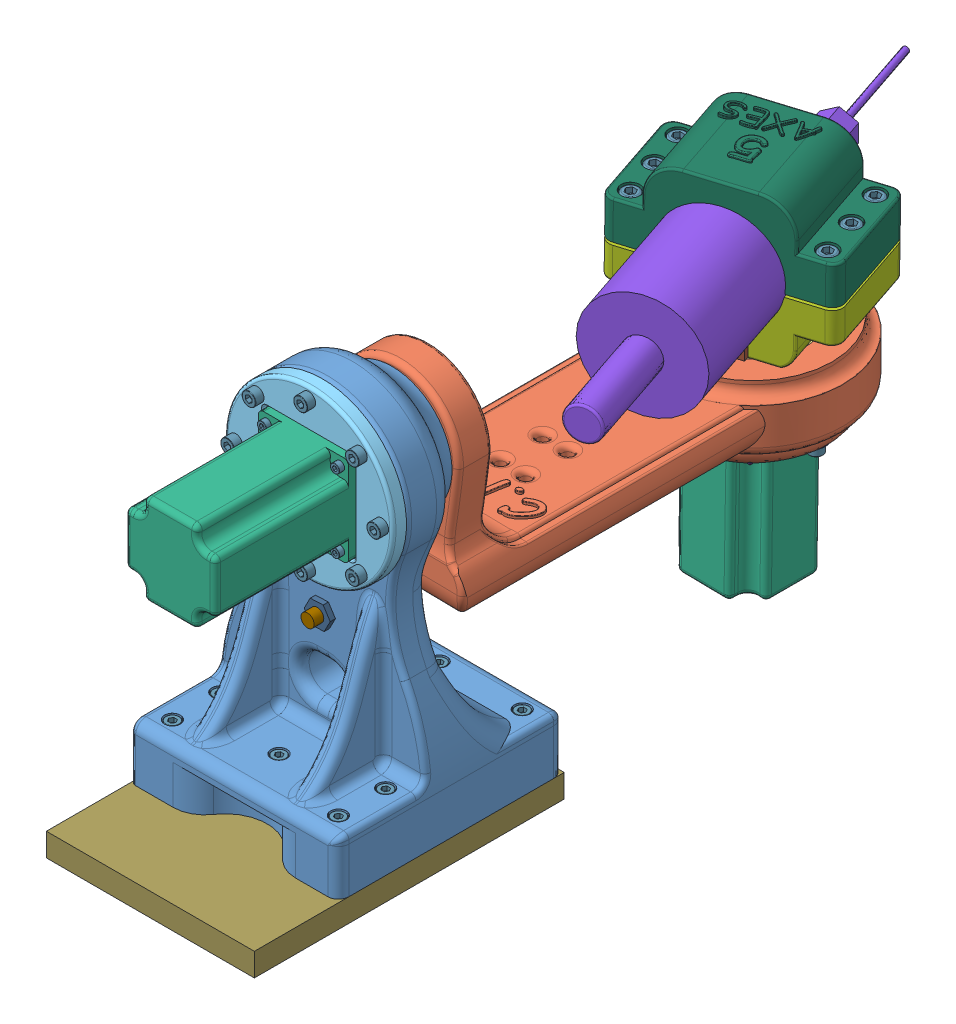
SolidWorks assembly tete 5 axes en mouvement, configuration Défaut. Lengths in mm.
Overall size (248.49 362.56 807.59).
70 component instances, 17 part files, 151 mates.
Components (placement in the parent):
- piece 1-1-1: piece 1-1 [Défaut] at (38.8935 -19.616 413.569) size (199.42 340.56 214.97)
- Pièce3^tete 5 axes-1: Pièce3^tete 5 axes [Défaut] at (37.1302 -19.7902 335.8451) x (0.999871 -0.01606 0) z (-0.01606 -0.999871 0) size (175.54 481.72 211.7)
- roulement piece 1-1: roulement piece 1 [Défaut] at (27.1666 90.0863 443.8984) x (-0.999728 0.023318 0) z (0 0 1) size (105 105 20)
- Pièce 1-3-1: Pièce 1-3 [Défaut] at (37.1302 -19.7902 463.8984) x (0.999871 -0.01606 0) z (0 0 1) size (80 80 10)
- Pièce1-2-1: Pièce1-2 [Défaut] at (38.8935 -19.616 479.8984) size (160 160 13)
- moteur-1: moteur [Défaut] at (38.8935 106.5111 487.8984) size (86 86 171)
- Pièce 2-3-1: Pièce 2-3 [Défaut] at (121.7091 79.1642 318.6411) x (0.948952 -0.015242 -0.315051) z (-0.01606 -0.999871 0) size (180 100.51 109.64)
- broche-1: broche [Défaut] at (79.1434 89.2514 227.1649) x (-0.949054 -0.010165 0.31495) z (-0.315011 0.00506 -0.949075) size (100 100 485)
- capteur fin de cource-3: capteur fin de cource [Défaut] at (39.937 11.1854 170.3888) x (0.960842 -0.015433 -0.276667) z (0.01606 0.999871 0) size (12.5 12.5 63.5)
- ecrous capteur fin de cource-6: ecrous capteur fin de cource [Défaut] at (40.8266 -18.5494 163.5015) x (0.782352 -0.012566 0.62271) z (-0.01606 -0.999871 0) size (24.76 22 5)
- ecrous capteur fin de cource-7: ecrous capteur fin de cource [Défaut] at (41.2392 7.1473 164.5494) x (0.738232 -0.011857 0.674443) z (-0.01606 -0.999871 0) size (24.76 22 5)
- Pièce 2-4-1: Pièce 2-4 [Défaut] at (53.925 82.1555 114.3268) x (0.948952 -0.015242 -0.315051) z (0.315011 -0.00506 0.949075) size (45 18.19 53)
- Pièce11^Assemblage1-1: Pièce11^Assemblage1 [Défaut] at (27.1666 -170.472 -625.5807) x (-1 0 0) z (0 1 0) size (198 294.97 22)
- Pièce1^tete 5 axes en mouvement-1: Pièce1^tete 5 axes en mouvement [Défaut] at (37.1302 -19.7902 413.5676) x (0.999871 -0.01606 0) z (0 0 1) size (56 23.61 15.05) (virtual)
- capteur fin de cource-4: capteur fin de cource [Défaut] at (12.6617 -27.2437 485.6222) x (-0.49685 -0.867836 0) z (0 0 1) size (12.5 12.5 63.5)
- ecrous capteur fin de cource-8: ecrous capteur fin de cource [Défaut] at (38.8935 -32.0352 479.8984) size (24.76 22 5)
- ecrous capteur fin de cource-9: ecrous capteur fin de cource [Défaut] at (38.8935 -32.0352 433.8984) size (24.76 22 5)
- socket head cap screw_iso-1: socket head cap screw_iso [ISO 4762 M8 x 12 - 12N] at (-42.3636 90.0863 500.8984) x (0 0 -1) z (1 0 0) size (20 13 13)
- socket head cap screw_iso-2: socket head cap screw_iso [ISO 4762 M8 x 12 - 12N] at (-21.9987 139.2516 500.8984) x (0 0 -1) z (1 0 0) size (20 13 13)
- socket head cap screw_iso-3: socket head cap screw_iso [ISO 4762 M8 x 12 - 12N] at (27.1666 159.6165 500.8984) x (0 0 -1) z (1 0 0) size (20 13 13)
- socket head cap screw_iso-4: socket head cap screw_iso [ISO 4762 M8 x 12 - 12N] at (76.3319 139.2516 500.8984) x (0 0 -1) z (1 0 0) size (20 13 13)
- socket head cap screw_iso-5: socket head cap screw_iso [ISO 4762 M8 x 12 - 12N] at (-21.9987 40.921 500.8984) x (0 0 -1) z (1 0 0) size (20 13 13)
- socket head cap screw_iso-6: socket head cap screw_iso [ISO 4762 M8 x 12 - 12N] at (27.1666 20.5561 500.8984) x (0 0 -1) z (1 0 0) size (20 13 13)
- socket head cap screw_iso-7: socket head cap screw_iso [ISO 4762 M8 x 12 - 12N] at (76.3319 40.921 500.8984) x (0 0 -1) z (1 0 0) size (20 13 13)
- socket head cap screw_iso-8: socket head cap screw_iso [ISO 4762 M8 x 12 - 12N] at (96.6968 90.0863 500.8984) x (0 0 -1) z (1 0 0) size (20 13 13)
- socket head cap screw_iso-9: socket head cap screw_iso [ISO 4762 M8 x 12 - 12N] at (44.4832 30.3982 125.6139) x (-0.315011 0.00506 -0.949075) z (0.757767 0.603439 -0.248296) size (20 13 13)
- socket head cap screw_iso-10: socket head cap screw_iso [ISO 4762 M8 x 12 - 12N] at (25.5654 -9.6032 426.2431) x (0 0 -1) z (0.999861 0.016693 0) size (20 13 13)
- roulement piece 1-2: roulement piece 1 [Défaut] at (27.1666 90.0863 413.5676) x (-0.999728 0.023318 0) z (0 0 1) size (105 105 20)
- roulement piece 1-3: roulement piece 1 [Défaut] at (25.6987 -1.3042 70.5676) x (-0.995697 0.015993 0.091282) z (0.01606 0.999871 0) size (105 105 20)
- bride broche-3: bride broche [Défaut] at (-67.6377 84.7058 -177.5059) x (0.948952 -0.015242 -0.315051) z (0.01606 0.999871 0) size (180 100 79.18)
- socket head cap screw_iso-19: socket head cap screw_iso [ISO 4762 M8 x 50 - 28N] at (106.1666 -119.072 368.7518) x (0 -1 0) z (0 0 1) size (58 13 13)
- socket head cap screw_iso-20: socket head cap screw_iso [ISO 4762 M8 x 50 - 28N] at (106.1304 -119.072 498.717) x (0 -1 0) z (0 0 1) size (58 13 13)
- socket head cap screw_iso-21: socket head cap screw_iso [ISO 4762 M8 x 50 - 28N] at (106.1666 -119.072 543.717) x (0 -1 0) z (0 0 1) size (58 13 13)
- socket head cap screw_iso-22: socket head cap screw_iso [ISO 4762 M8 x 50 - 28N] at (27.1666 -119.072 521.217) x (0 -1 0) z (0 0 1) size (58 13 13)
- socket head cap screw_iso-23: socket head cap screw_iso [ISO 4762 M8 x 50 - 28N] at (-51.8334 -119.072 543.717) x (0 -1 0) z (0 0 1) size (58 13 13)
- socket head cap screw_iso-24: socket head cap screw_iso [ISO 4762 M8 x 50 - 28N] at (-51.7972 -119.072 498.717) x (0 -1 0) z (0 0 1) size (58 13 13)
- socket head cap screw_iso-25: socket head cap screw_iso [ISO 4762 M8 x 50 - 28N] at (-51.8334 -119.072 368.7518) x (0 -1 0) z (0 0 1) size (58 13 13)
- socket head cap screw_iso-26: socket head cap screw_iso [ISO 4762 M8 x 50 - 28N] at (27.1666 -119.072 368.7518) x (0 -1 0) z (0 0 1) size (58 13 13)
- socket head cap screw_iso-33: socket head cap screw_iso [ISO 4762 M10 x 60 - 32N] at (-31.5726 119.7311 127.8903) x (-0.01606 -0.999871 0) z (0 0 1) size (70 16 16)
- socket head cap screw_iso-34: socket head cap screw_iso [ISO 4762 M10 x 60 - 32N] at (-42.8342 119.912 93.9608) x (-0.01606 -0.999871 0) z (0 0 1) size (70 16 16)
- socket head cap screw_iso-35: socket head cap screw_iso [ISO 4762 M10 x 60 - 32N] at (-54.0958 120.0929 60.0314) x (-0.01606 -0.999871 0) z (0.876134 -0.014072 -0.481862) size (70 16 16)
- socket head cap screw_iso-36: socket head cap screw_iso [ISO 4762 M10 x 60 - 32N] at (86.8276 117.8294 13.245) x (-0.01606 -0.999871 0) z (-0.018104 0.000291 0.999836) size (70 16 16)
- socket head cap screw_iso-37: socket head cap screw_iso [ISO 4762 M10 x 60 - 32N] at (98.0892 117.6485 47.1744) x (-0.01606 -0.999871 0) z (-0.018104 0.000291 0.999836) size (70 16 16)
- socket head cap screw_iso-38: socket head cap screw_iso [ISO 4762 M10 x 60 - 32N] at (109.3508 117.4676 81.1038) x (-0.01606 -0.999871 0) z (-0.018104 0.000291 0.999836) size (70 16 16)
- roulement piece 1-4: roulement piece 1 [Défaut] at (25.2651 -28.3008 70.5676) x (-0.995697 0.015993 0.091282) z (0.01606 0.999871 0) size (105 105 20)
- Pièce 2-2-3: Pièce 2-2 [Défaut] at (-47.3003 -35.1363 -184.8951) x (0.948952 -0.015242 -0.315051) z (0.01606 0.999871 0) size (80 80 8)
- socket head cap screw_iso-39: socket head cap screw_iso [ISO 4762 M8 x 12 - 12N] at (10.0611 -44.0586 87.3837) x (0.01606 0.999871 0) z (0 0 1) size (20 13 13)
- socket head cap screw_iso-40: socket head cap screw_iso [ISO 4762 M8 x 12 - 12N] at (32.0959 -44.4125 91.9218) x (0.01606 0.999871 0) z (0 0 1) size (20 13 13)
- socket head cap screw_iso-41: socket head cap screw_iso [ISO 4762 M8 x 12 - 12N] at (47.0429 -44.6526 75.1058) x (0.01606 0.999871 0) z (0 0 1) size (20 13 13)
- socket head cap screw_iso-42: socket head cap screw_iso [ISO 4762 M8 x 12 - 12N] at (39.9552 -44.5388 53.7516) x (0.01606 0.999871 0) z (0 0 1) size (20 13 13)
- socket head cap screw_iso-43: socket head cap screw_iso [ISO 4762 M8 x 12 - 12N] at (17.9204 -44.1849 49.2134) x (0.01606 0.999871 0) z (-0.345842 0.005555 0.938276) size (20 13 13)
- socket head cap screw_iso-44: socket head cap screw_iso [ISO 4762 M8 x 12 - 12N] at (2.9734 -43.9448 66.0295) x (0.01606 0.999871 0) z (0 0 1) size (20 13 13)
- plaque fixation moteur-2: plaque fixation moteur [Défaut] at (24.9921 -45.2986 70.5676) x (0.999871 -0.01606 0) z (-0.01606 -0.999871 0) size (145.6 105 10.28)
- socket head cap screw_iso-45: socket head cap screw_iso [ISO 4762 M8 x 12 - 12N] at (87.5176 -64.3052 70.5676) x (0.01606 0.999871 0) z (0 0 1) size (20 13 13)
- socket head cap screw_iso-46: socket head cap screw_iso [ISO 4762 M8 x 12 - 12N] at (-38.1115 -62.2873 70.5676) x (0.01606 0.999871 0) z (0 0 1) size (20 13 13)
- moteur-6: moteur [Défaut] at (41.3345 -50.5617 58.8407) x (0 0 -1) z (-0.01606 -0.999871 0) size (86 86 171)
- socket head cap screw_iso-48: socket head cap screw_iso [ISO 4762 M5 x 16 - 16N] at (-10.1246 -64.7371 35.7676) x (0.01606 0.999871 0) z (0 0 1) size (21 8.5 8.5)
- socket head cap screw_iso-49: socket head cap screw_iso [ISO 4762 M5 x 16 - 16N] at (-10.1246 -64.7371 105.3676) x (0.01606 0.999871 0) z (0 0 1) size (21 8.5 8.5)
- socket head cap screw_iso-51: socket head cap screw_iso [ISO 4762 M5 x 16 - 16N] at (59.4664 -65.8549 35.7676) x (0.01606 0.999871 0) z (0 0 1) size (21 8.5 8.5)
- socket head cap screw_iso-52: socket head cap screw_iso [ISO 4762 M5 x 16 - 16N] at (59.4664 -65.8549 105.3676) x (0.01606 0.999871 0) z (0 0 1) size (21 8.5 8.5)
- socket head cap screw_iso-53: socket head cap screw_iso [ISO 4762 M5 x 20 - 20N] at (-7.6334 55.2863 502.8984) x (0 0 -1) z (-0.00216 0.999998 0) size (25 8.5 8.5)
- socket head cap screw_iso-54: socket head cap screw_iso [ISO 4762 M5 x 20 - 20N] at (61.9666 55.2863 502.8984) x (0 0 -1) z (-0.00216 0.999998 0) size (25 8.5 8.5)
- socket head cap screw_iso-55: socket head cap screw_iso [ISO 4762 M5 x 20 - 20N] at (61.9666 124.8863 502.8984) x (0 0 -1) z (-0.00216 0.999998 0) size (25 8.5 8.5)
- socket head cap screw_iso-56: socket head cap screw_iso [ISO 4762 M5 x 20 - 20N] at (-7.6334 124.8863 502.8984) x (0 0 -1) z (-0.00216 0.999998 0) size (25 8.5 8.5)
- socket head cap screw_iso-57: socket head cap screw_iso [ISO 4762 M8 x 12 - 12N] at (26.8085 67.7885 481.8984) x (0 0 -1) z (1 0 0) size (20 13 13)
- socket head cap screw_iso-58: socket head cap screw_iso [ISO 4762 M8 x 12 - 12N] at (7.6771 79.2475 481.8984) x (0 0 -1) z (1 0 0) size (20 13 13)
- socket head cap screw_iso-59: socket head cap screw_iso [ISO 4762 M8 x 12 - 12N] at (8.0352 101.5453 481.8984) x (0 0 -1) z (1 0 0) size (20 13 13)
- socket head cap screw_iso-60: socket head cap screw_iso [ISO 4762 M8 x 12 - 12N] at (27.5248 112.3841 481.8984) x (0 0 -1) z (1 0 0) size (20 13 13)
- socket head cap screw_iso-61: socket head cap screw_iso [ISO 4762 M8 x 12 - 12N] at (46.6561 100.925 481.8984) x (0 0 -1) z (1 0 0) size (20 13 13)
- socket head cap screw_iso-62: socket head cap screw_iso [ISO 4762 M8 x 12 - 12N] at (46.298 78.6272 481.8984) x (0 0 -1) z (1 0 0) size (20 13 13)
Mates (geometry in assembly coordinates):
- Coaxiale1: concentric: cylinder of piece 1-1-1 through (27.1666 90.0863 417.8676) axis (0 0 1) radius 37.5; cylinder of ? through (52.9513 121.883 507.2824) axis (0 0 -1) radius 37.5
- Coïncidente1: coincident: plane of assembly; plane of assembly; plane of piece 1-1-1 through (27.1666 90.0863 413.5676) normal (0 0 -1); plane of Pièce3^tete 5 axes-1 through (-26.936 33.8633 413.5676) normal (0 0 1)
- Coaxiale2: concentric: cylinder of ? through (52.9513 121.883 507.2824) axis (0 0 -1) radius 37.5; cylinder of ? through (27.1666 90.0863 468.8984) axis (0 0 -1) radius 30
- Coïncidente2: coincident: plane of piece 1-1-1 through (27.1666 90.0863 443.8984) normal (0 0 1); plane of ? through (27.1666 90.0863 443.8984) normal (0 0 -1)
- Coïncidente3: coincident: plane of assembly; plane of assembly; plane of piece 1-1-1 through (27.1666 90.0863 463.8984) normal (0 0 1); plane of Pièce 1-3-1 through (27.1666 90.0863 463.8984) normal (0 0 -1)
- Coaxiale3: concentric: cylinder of piece 1-1-1 through (27.1666 90.0863 473.8984) axis (0 0 -1) radius 62.3193; cylinder of ? through (27.1666 90.0863 473.8984) axis (0 0 -1) radius 62.3193
- Coaxiale4: concentric: cylinder of assembly; cylinder of assembly; cylinder of Pièce3^tete 5 axes-1 through (27.5248 112.3841 419.897) axis (0 0 1) radius 3.25; cylinder of Pièce 1-3-1 through (27.5248 112.3841 419.8984) axis (0 0 1) radius 3.25
- Coaxiale5: concentric: cylinder of assembly; cylinder of assembly; cylinder of piece 1-1-1 through (27.1666 90.0863 212.6243) axis (0 0 1) radius 80; cylinder of Pièce1-2-1 through (27.1666 90.0863 492.8984) axis (0 0 -1) radius 80
- Coïncidente4: coincident: plane of assembly; plane of assembly; plane of piece 1-1-1 through (27.1666 90.0863 479.8984) normal (0 0 1); plane of Pièce1-2-1 through (27.1666 90.0863 479.8984) normal (0 0 -1)
- Coaxiale6: concentric: cylinder of assembly; cylinder of assembly; cylinder of Pièce1-2-1 through (27.1666 90.0863 492.8984) axis (0 0 -1) radius 17.0688; cylinder of moteur-1 through (27.1666 90.0863 453.8984) axis (0 0 1) radius 7
- Parallèle1: parallel: plane of assembly; plane of assembly; plane of Pièce 2-3-1 through (-43.6353 19.812 146.376) normal (-0.948952 0.015242 0.315051); plane of broche-1 through (-27.8922 82.4695 -48.1738) normal (-0.948952 0.015242 0.315051)
- Coaxiale20: concentric: cylinder of assembly; cylinder of assembly; cylinder of Pièce3^tete 5 axes-1 through (26.3363 38.3906 164.0236) axis (-0.01606 -0.999871 0) radius 6.25; cylinder of capteur fin de cource-3 through (25.0197 -43.5821 164.0236) axis (0.01606 0.999871 0) radius 6.25
- Coaxiale21: concentric: cylinder of capteur fin de cource-3 through (25.0197 -43.5821 164.0236) axis (0.01606 0.999871 0) radius 6.25; cylinder of ecrous capteur fin de cource-6 through (25.3454 -23.3014 164.0236) axis (0.01606 0.999871 0) radius 6.25
- Coïncidente19: coincident: plane of Pièce3^tete 5 axes-1 through (37.1511 -18.4904 335.8451) normal (-0.01606 -0.999871 0); plane of ecrous capteur fin de cource-6 through (40.8266 -18.5494 163.5015) normal (0.01606 0.999871 0)
- Coaxiale22: concentric: cylinder of capteur fin de cource-3 through (25.0197 -43.5821 164.0236) axis (0.01606 0.999871 0) radius 6.25; cylinder of ecrous capteur fin de cource-7 through (25.7581 2.3953 164.0236) axis (0.01606 0.999871 0) radius 6.25
- Coïncidente21: coincident: plane of Pièce3^tete 5 axes-1 through (25.7581 2.3953 164.0236) normal (0.01606 0.999871 0); plane of ecrous capteur fin de cource-7 through (41.1589 2.1479 164.5494) normal (-0.01606 -0.999871 0)
- Coïncidente23: coincident: plane of assembly; plane of assembly; plane of Pièce 2-3-1 through (-43.6353 19.812 146.376) normal (0.315011 -0.00506 0.949075); plane of Pièce 2-4-1 through (53.925 82.1555 114.3268) normal (-0.315011 0.00506 -0.949075)
- Largeur4: width: plane of Pièce 2-3-1 through (-43.6353 19.812 146.376) normal (-0.948952 0.015242 0.315051); plane of Pièce 2-3-1 through (127.1762 17.0684 89.6667) normal (0.948952 -0.015242 -0.315051); plane of Pièce 2-4-1 through (22.0969 25.1593 129.8554) normal (-0.948952 0.015242 0.315051); plane of Pièce 2-4-1 through (64.7997 24.4734 115.6781) normal (0.948952 -0.015242 -0.315051)
- Distance3: distance = 2 mm: plane of capteur fin de cource-3 through (26.0395 19.9101 164.0236) normal (0.01606 0.999871 0); plane of Pièce 2-4-1 through (88.6934 20.904 123.5345) normal (-0.01606 -0.999871 0)
- Distance5: distance = 10 mm: plane of assembly; plane of assembly; plane of broche-1 through (8.266 90.3898 13.6231) normal (-0.315011 0.00506 -0.949075); plane of Pièce 2-3-1 through (-75.1363 20.3179 51.4685) normal (-0.315011 0.00506 -0.949075)
- Sur place1: in place: plane of ? through (-31.8614 141.1138 413.5676) normal (0 0 1); plane of ? through (0 0 413.5676) normal (0 0 1); moOrthogonalPlaneRef_w of ? through (-31.8614 141.1138 413.5676) normal (0 0 1); plane of ? through (0 0 413.5676) normal (0 1 0); plane of ? through (-31.8614 141.1138 413.5676) normal (0 0 1); plane of ? through (0 0 413.5676) normal (1 0 0); plane of Pièce3^tete 5 axes-1 through (-26.936 33.8633 413.5676) normal (0 0 1); unknown of Pièce1^tete 5 axes en mouvement-1
- Coïncidente36: coincident: plane of assembly; plane of assembly; plane of Pièce3^tete 5 axes-1; plane of Pièce1^tete 5 axes en mouvement-1
- Coïncidente37: coincident: plane of assembly; plane of assembly; moOrthogonalPlaneRef_w of Pièce3^tete 5 axes-1; plane of Pièce1^tete 5 axes en mouvement-1 through (37.1302 -19.7902 413.5676) normal (0.01606 0.999871 0)
- Coïncidente38: coincident: plane of assembly; plane of assembly; moOrthogonalPlaneRef_w of Pièce3^tete 5 axes-1; plane of Pièce1^tete 5 axes en mouvement-1 through (37.1302 -19.7902 413.5676) normal (0.999871 -0.01606 0)
- Coaxiale25: concentric: cylinder of assembly; cylinder of assembly; cylinder of piece 1-1-1 through (27.1666 -22.0352 413.8984) axis (0 0 1) radius 6.25; cylinder of capteur fin de cource-4 through (27.1666 -22.0352 430.6222) axis (0 0 1) radius 6.25
- Distance6: distance = 2 mm: plane of capteur fin de cource-4 through (27.1666 -22.0352 430.6222) normal (0 0 -1); plane of Pièce1^tete 5 axes en mouvement-1 through (37.1302 -19.7902 428.6222) normal (0 0 1)
- Coïncidente41: coincident: plane of assembly; plane of assembly; plane of piece 1-1-1 through (27.1666 90.0863 479.8984) normal (0 0 1); plane of ecrous capteur fin de cource-8 through (38.8935 -32.0352 479.8984) normal (0 0 -1)
- Coaxiale26: concentric: cylinder of capteur fin de cource-4 through (27.1666 -22.0352 430.6222) axis (0 0 1) radius 6.25; cylinder of ecrous capteur fin de cource-8 through (27.1666 -22.0352 484.8984) axis (0 0 -1) radius 6.25
- Coïncidente42: coincident: plane of assembly; plane of assembly; plane of piece 1-1-1 through (27.1666 90.0863 438.8984) normal (0 0 -1); plane of ecrous capteur fin de cource-9 through (38.8935 -32.0352 438.8984) normal (0 0 1)
- Coaxiale27: concentric: cylinder of capteur fin de cource-4 through (27.1666 -22.0352 430.6222) axis (0 0 1) radius 6.25; cylinder of ecrous capteur fin de cource-9 through (27.1666 -22.0352 438.8984) axis (0 0 -1) radius 6.25
- Coaxiale28: concentric: cylinder of assembly; cylinder of assembly; cylinder of Pièce1-2-1 through (-42.3636 90.0863 457.8984) axis (0 0 1) radius 3.6; cylinder of socket head cap screw_iso-1 through (-42.3636 90.0863 532.6484) axis (0 0 1) radius 6.5
- Coïncidente43: coincident: plane of Pièce1-2-1 through (27.1666 90.0863 492.8984) normal (0 0 1); plane of socket head cap screw_iso-1 through (-42.3636 96.5863 492.8984) normal (0 0 -1)
- Coaxiale29: concentric: cylinder of assembly; cylinder of assembly; cylinder of Pièce1-2-1 through (-21.9987 139.2516 457.8984) axis (0 0 1) radius 3.6; cylinder of socket head cap screw_iso-2 through (-21.9987 139.2516 532.6484) axis (0 0 1) radius 6.5
- Coïncidente44: coincident: plane of Pièce1-2-1 through (27.1666 90.0863 492.8984) normal (0 0 1); plane of socket head cap screw_iso-2 through (-21.9987 145.7516 492.8984) normal (0 0 -1)
- Coaxiale30: concentric: cylinder of assembly; cylinder of assembly; cylinder of Pièce1-2-1 through (27.1666 159.6165 457.8984) axis (0 0 1) radius 3.6; cylinder of socket head cap screw_iso-3 through (27.1666 159.6165 532.6484) axis (0 0 1) radius 6.5
- Coïncidente45: coincident: plane of Pièce1-2-1 through (27.1666 90.0863 492.8984) normal (0 0 1); plane of socket head cap screw_iso-3 through (27.1666 166.1165 492.8984) normal (0 0 -1)
- Coaxiale31: concentric: cylinder of assembly; cylinder of assembly; cylinder of Pièce1-2-1 through (76.3319 139.2516 457.8984) axis (0 0 1) radius 3.6; cylinder of socket head cap screw_iso-4 through (76.3319 139.2516 532.6484) axis (0 0 1) radius 6.5
- Coïncidente46: coincident: plane of Pièce1-2-1 through (27.1666 90.0863 492.8984) normal (0 0 1); plane of socket head cap screw_iso-4 through (76.3319 145.7516 492.8984) normal (0 0 -1)
- Coaxiale32: concentric: cylinder of assembly; cylinder of assembly; cylinder of Pièce1-2-1 through (-21.9987 40.921 457.8984) axis (0 0 1) radius 3.6; cylinder of socket head cap screw_iso-5 through (-21.9987 40.921 532.6484) axis (0 0 1) radius 6.5
- Coïncidente47: coincident: plane of Pièce1-2-1 through (27.1666 90.0863 492.8984) normal (0 0 1); plane of socket head cap screw_iso-5 through (-21.9987 47.421 492.8984) normal (0 0 -1)
- Coaxiale33: concentric: cylinder of assembly; cylinder of assembly; cylinder of Pièce1-2-1 through (27.1666 20.5561 457.8984) axis (0 0 1) radius 3.6; cylinder of socket head cap screw_iso-6 through (27.1666 20.5561 532.6484) axis (0 0 1) radius 6.5
- Coïncidente48: coincident: plane of Pièce1-2-1 through (27.1666 90.0863 492.8984) normal (0 0 1); plane of socket head cap screw_iso-6 through (27.1666 27.0561 492.8984) normal (0 0 -1)
- Coaxiale34: concentric: cylinder of assembly; cylinder of assembly; cylinder of Pièce1-2-1 through (76.3319 40.921 457.8984) axis (0 0 1) radius 3.6; cylinder of socket head cap screw_iso-7 through (76.3319 40.921 532.6484) axis (0 0 1) radius 6.5
- Coïncidente49: coincident: plane of Pièce1-2-1 through (27.1666 90.0863 492.8984) normal (0 0 1); plane of socket head cap screw_iso-7 through (76.3319 47.421 492.8984) normal (0 0 -1)
- Coaxiale35: concentric: cylinder of assembly; cylinder of assembly; cylinder of Pièce1-2-1 through (96.6968 90.0863 457.8984) axis (0 0 1) radius 3.6; cylinder of socket head cap screw_iso-8 through (96.6968 90.0863 532.6484) axis (0 0 1) radius 6.5
- Coïncidente50: coincident: plane of Pièce1-2-1 through (27.1666 90.0863 492.8984) normal (0 0 1); plane of socket head cap screw_iso-8 through (96.6968 96.5863 492.8984) normal (0 0 -1)
- Coaxiale36: concentric: cylinder of assembly; cylinder of assembly; cylinder of Pièce 2-3-1 through (35.663 30.5398 99.0399) axis (0.315011 -0.00506 0.949075) radius 3.6; cylinder of socket head cap screw_iso-9 through (54.4848 30.2375 155.7471) axis (0.315011 -0.00506 0.949075) radius 6.5
- Coïncidente51: coincident: plane of Pièce 2-3-1 through (-43.6353 19.812 146.376) normal (0.315011 -0.00506 0.949075); plane of socket head cap screw_iso-9 through (38.2487 35.6217 119.2819) normal (-0.315011 0.00506 -0.949075)
- Coaxiale37: concentric: cylinder of assembly; cylinder of assembly; cylinder of Pièce3^tete 5 axes-1 through (25.5654 -9.6032 388.5676) axis (0 0 1) radius 3.6; cylinder of socket head cap screw_iso-10 through (25.5654 -9.6032 457.9931) axis (0 0 1) radius 6.5
- Coïncidente52: coincident: plane of assembly; plane of assembly; plane of piece 1-1-1 through (27.1666 90.0863 443.8984) normal (0 0 1); plane of roulement piece 1-1 through (27.1666 90.0863 443.8984) normal (0 0 -1)
- Coaxiale38: concentric: cylinder of assembly; cylinder of assembly; cylinder of Pièce3^tete 5 axes-1 through (27.1666 90.0863 507.2824) axis (0 0 -1) radius 37.5; cylinder of roulement piece 1-1 through (27.1666 90.0863 463.8984) axis (0 0 -1) radius 37.5
- Coïncidente53: coincident: plane of assembly; plane of assembly; plane of piece 1-1-1 through (27.1666 90.0863 433.5676) normal (0 0 -1); plane of roulement piece 1-2 through (27.1666 90.0863 433.5676) normal (0 0 1)
- Coaxiale39: concentric: cylinder of Pièce3^tete 5 axes-1 through (27.1666 90.0863 507.2824) axis (0 0 -1) radius 37.5; cylinder of roulement piece 1-2 through (27.1666 90.0863 433.5676) axis (0 0 -1) radius 37.5
- Coaxiale41: concentric: cylinder of piece 1-1-1 through (27.1666 90.0863 433.5676) axis (0 0 -1) radius 52.5; cylinder of roulement piece 1-2 through (27.1666 90.0863 433.5676) axis (0 0 -1) radius 52.5
- Coaxiale421: concentric: cylinder of assembly; cylinder of assembly; cylinder of Pièce3^tete 5 axes-1 through (23.3252 -149.0776 70.5676) axis (0.01606 0.999871 0) radius 52.5; cylinder of roulement piece 1-3 through (26.0199 18.6932 70.5676) axis (-0.01606 -0.999871 0) radius 52.5
- Coïncidente541: coincident: plane of assembly; plane of assembly; plane of Pièce3^tete 5 axes-1 through (25.6987 -1.3042 70.5676) normal (0.01606 0.999871 0); plane of roulement piece 1-3 through (25.6987 -1.3042 70.5676) normal (-0.01606 -0.999871 0)
- Coïncidente551: coincident: plane of assembly; plane of assembly; plane of Pièce 2-3-1 through (120.7134 17.1722 318.6411) normal (-0.01606 -0.999871 0); plane of roulement piece 1-3 through (26.0199 18.6932 70.5676) normal (0.01606 0.999871 0)
- Coaxiale461: concentric: cylinder of assembly; cylinder of assembly; cylinder of Pièce 2-3-1 through (27.7233 124.7455 70.5676) axis (-0.01606 -0.999871 0) radius 37.5; cylinder of roulement piece 1-3 through (26.0199 18.6932 70.5676) axis (-0.01606 -0.999871 0) radius 37.5
- Coaxiale481: concentric: cylinder of assembly; cylinder of assembly; cylinder of piece 1-1-1 through (27.1666 90.0863 212.6243) axis (0 0 1) radius 80; cylinder of Pièce3^tete 5 axes-1 through (27.1666 90.0863 378.5676) axis (0 0 1) radius 60
- Tangent61: tangent: cylinder of broche-1 through (8.266 90.3898 13.6231) axis (0.315011 -0.00506 0.949075) radius 50; plane of Pièce 2-4-1 through (65.0406 39.4715 115.6781) normal (0.01606 0.999871 0)
- Tangent71: tangent: cylinder of assembly; cylinder of assembly; cylinder of Pièce 2-3-1 through (-5.9095 90.6175 -29.0852) axis (0.315011 -0.00506 0.949075) radius 50; cylinder of broche-1 through (8.266 90.3898 13.6231) axis (0.315011 -0.00506 0.949075) radius 50
- Distance111: distance = 2.5 mm: plane of assembly; plane of assembly; plane of bride broche-3 through (-61.4608 84.6066 57.8087) normal (-0.01606 -0.999871 0); plane of Pièce 2-3-1 through (121.7091 79.1642 318.6411) normal (0.01606 0.999871 0)
- Coïncidente651: coincident: plane of assembly; plane of assembly; plane of Pièce 2-3-1 through (-43.6353 19.812 146.376) normal (-0.948952 0.015242 0.315051); plane of bride broche-3 through (-44.5129 161.3443 136.8852) normal (-0.948952 0.015242 0.315051)
- Coïncidente661: coincident: plane of assembly; plane of assembly; plane of Pièce 2-3-1 through (-75.1363 20.3179 51.4685) normal (-0.315011 0.00506 -0.949075); plane of bride broche-3 through (-63.3744 161.6473 48.318) normal (-0.315011 0.00506 -0.949075)
- Parallèle101: parallel: plane of assembly; plane of assembly; plane of piece 1-1-1 through (-71.6381 -118.472 593.627) normal (0 1 0); plane of moteur-1 through (-15.8334 47.0863 624.8984) normal (0 -1 0)
- Coaxiale637: concentric: cylinder of assembly; cylinder of assembly; cylinder of piece 1-1-1 through (106.1666 -118.472 368.7518) axis (0 1 0) radius 4.5; cylinder of socket head cap screw_iso-19 through (106.1666 -87.322 368.7518) axis (0 1 0) radius 6.5
- Coïncidente700: coincident: plane of assembly; plane of assembly; plane of piece 1-1-1 through (113.6666 -127.072 368.7518) normal (0 1 0); plane of socket head cap screw_iso-19 through (112.6666 -127.072 368.7518) normal (0 -1 0)
- Coaxiale638: concentric: cylinder of assembly; cylinder of assembly; cylinder of piece 1-1-1 through (106.1304 -118.472 498.717) axis (0 1 0) radius 4.5; cylinder of socket head cap screw_iso-20 through (106.1304 -87.322 498.717) axis (0 1 0) radius 6.5
- Coïncidente701: coincident: plane of assembly; plane of assembly; plane of piece 1-1-1 through (113.6304 -127.072 498.717) normal (0 1 0); plane of socket head cap screw_iso-20 through (112.6304 -127.072 498.717) normal (0 -1 0)
- Coaxiale639: concentric: cylinder of assembly; cylinder of assembly; cylinder of piece 1-1-1 through (106.1666 -118.472 543.717) axis (0 1 0) radius 4.5; cylinder of socket head cap screw_iso-21 through (106.1666 -87.322 543.717) axis (0 1 0) radius 6.5
- Coïncidente702: coincident: plane of assembly; plane of assembly; plane of piece 1-1-1 through (113.6666 -127.072 543.717) normal (0 1 0); plane of socket head cap screw_iso-21 through (112.6666 -127.072 543.717) normal (0 -1 0)
- Coaxiale640: concentric: cylinder of assembly; cylinder of assembly; cylinder of piece 1-1-1 through (27.1666 -118.472 521.217) axis (0 1 0) radius 4.5; cylinder of socket head cap screw_iso-22 through (27.1666 -87.322 521.217) axis (0 1 0) radius 6.5
- Coïncidente703: coincident: plane of assembly; plane of assembly; plane of piece 1-1-1 through (34.6666 -127.072 521.217) normal (0 1 0); plane of socket head cap screw_iso-22 through (33.6666 -127.072 521.217) normal (0 -1 0)
- Coaxiale641: concentric: cylinder of assembly; cylinder of assembly; cylinder of piece 1-1-1 through (-51.8334 -118.472 543.717) axis (0 1 0) radius 4.5; cylinder of socket head cap screw_iso-23 through (-51.8334 -87.322 543.717) axis (0 1 0) radius 6.5
- Coïncidente704: coincident: plane of assembly; plane of assembly; plane of piece 1-1-1 through (-44.3334 -127.072 543.717) normal (0 1 0); plane of socket head cap screw_iso-23 through (-45.3334 -127.072 543.717) normal (0 -1 0)
- Coaxiale642: concentric: cylinder of assembly; cylinder of assembly; cylinder of piece 1-1-1 through (-51.7972 -118.472 498.717) axis (0 1 0) radius 4.5; cylinder of socket head cap screw_iso-24 through (-51.7972 -87.322 498.717) axis (0 1 0) radius 6.5
- Coïncidente705: coincident: plane of assembly; plane of assembly; plane of piece 1-1-1 through (-44.2972 -127.072 498.717) normal (0 1 0); plane of socket head cap screw_iso-24 through (-45.2972 -127.072 498.717) normal (0 -1 0)
- Coaxiale643: concentric: cylinder of assembly; cylinder of assembly; cylinder of piece 1-1-1 through (-51.8334 -118.472 368.7518) axis (0 1 0) radius 7.5; cylinder of socket head cap screw_iso-25 through (-51.8334 -87.322 368.7518) axis (0 1 0) radius 6.5
- Coïncidente706: coincident: plane of assembly; plane of assembly; plane of piece 1-1-1 through (-44.3334 -127.072 368.7518) normal (0 1 0); plane of socket head cap screw_iso-25 through (-45.3334 -127.072 368.7518) normal (0 -1 0)
- Coaxiale644: concentric: cylinder of assembly; cylinder of assembly; cylinder of piece 1-1-1 through (27.1666 -118.472 368.7518) axis (0 1 0) radius 7.5; cylinder of socket head cap screw_iso-26 through (27.1666 -87.322 368.7518) axis (0 1 0) radius 6.5
- Coïncidente707: coincident: plane of assembly; plane of assembly; plane of piece 1-1-1 through (34.6666 -127.072 368.7518) normal (0 1 0); plane of socket head cap screw_iso-26 through (33.6666 -127.072 368.7518) normal (0 -1 0)
- Coaxiale651: concentric: cylinder of assembly; cylinder of assembly; cylinder of bride broche-3 through (-31.5629 120.331 127.8903) axis (0.01606 0.999871 0) radius 9; cylinder of socket head cap screw_iso-33 through (-31.0627 151.477 127.8903) axis (0.01606 0.999871 0) radius 8
- Coïncidente714: coincident: plane of assembly; plane of assembly; plane of bride broche-3 through (-23.1926 109.5952 125.0548) normal (0.01606 0.999871 0); plane of socket head cap screw_iso-33 through (-23.7342 109.6039 127.8903) normal (-0.01606 -0.999871 0)
- Coaxiale6521: concentric: cylinder of assembly; cylinder of assembly; cylinder of bride broche-3 through (-42.8246 120.5119 93.9608) axis (0.01606 0.999871 0) radius 9; cylinder of socket head cap screw_iso-34 through (-42.3243 151.6579 93.9608) axis (0.01606 0.999871 0) radius 8
- Coïncidente7151: coincident: plane of assembly; plane of assembly; plane of bride broche-3 through (-34.4542 109.7761 91.1254) normal (0.01606 0.999871 0); plane of socket head cap screw_iso-34 through (-34.9958 109.7848 93.9608) normal (-0.01606 -0.999871 0)
- Coaxiale6531: concentric: cylinder of assembly; cylinder of assembly; cylinder of bride broche-3 through (-54.0862 120.6928 60.0314) axis (0.01606 0.999871 0) radius 9; cylinder of socket head cap screw_iso-35 through (-53.5859 151.8388 60.0314) axis (0.01606 0.999871 0) radius 8
- Coïncidente7161: coincident: plane of assembly; plane of assembly; plane of bride broche-3 through (-45.7159 109.957 57.196) normal (0.01606 0.999871 0); plane of socket head cap screw_iso-35 through (-58.1108 110.1561 53.0214) normal (-0.01606 -0.999871 0)
- Coaxiale6541: concentric: cylinder of assembly; cylinder of assembly; cylinder of bride broche-3 through (86.8372 118.4293 13.245) axis (0.01606 0.999871 0) radius 9; cylinder of socket head cap screw_iso-36 through (87.3374 149.5753 13.245) axis (0.01606 0.999871 0) radius 8
- Coïncidente7171: coincident: plane of assembly; plane of assembly; plane of bride broche-3 through (95.2075 107.6935 10.4095) normal (0.01606 0.999871 0); plane of socket head cap screw_iso-36 through (94.6646 107.7022 13.3898) normal (-0.01606 -0.999871 0)
- Coaxiale6551: concentric: cylinder of assembly; cylinder of assembly; cylinder of bride broche-3 through (98.7541 159.0432 47.1744) axis (-0.01606 -0.999871 0) radius 6; cylinder of socket head cap screw_iso-37 through (98.5991 149.3944 47.1744) axis (0.01606 0.999871 0) radius 8
- Coïncidente7181: coincident: plane of assembly; plane of assembly; plane of bride broche-3 through (106.4692 107.5126 44.3389) normal (0.01606 0.999871 0); plane of socket head cap screw_iso-37 through (105.9262 107.5214 47.3192) normal (-0.01606 -0.999871 0)
- Coaxiale6561: concentric: cylinder of assembly; cylinder of assembly; cylinder of bride broche-3 through (110.0157 158.8623 81.1038) axis (-0.01606 -0.999871 0) radius 6; cylinder of socket head cap screw_iso-38 through (109.8607 149.2136 81.1038) axis (0.01606 0.999871 0) radius 8
- Coïncidente7191: coincident: plane of assembly; plane of assembly; plane of bride broche-3 through (117.7308 107.3318 78.2684) normal (0.01606 0.999871 0); plane of socket head cap screw_iso-38 through (117.1879 107.3405 81.2487) normal (-0.01606 -0.999871 0)
- Coïncidente7192: coincident: plane of assembly; plane of assembly; plane of Pièce3^tete 5 axes-1 through (25.5863 -8.3033 70.5676) normal (-0.01606 -0.999871 0); plane of roulement piece 1-4 through (25.5863 -8.3033 70.5676) normal (0.01606 0.999871 0)
- Coaxiale6562: concentric: cylinder of assembly; cylinder of assembly; cylinder of Pièce3^tete 5 axes-1 through (25.5863 -8.3033 70.5676) axis (-0.01606 -0.999871 0) radius 52.5; cylinder of roulement piece 1-4 through (25.5863 -8.3033 70.5676) axis (-0.01606 -0.999871 0) radius 52.5
- Coïncidente7193: coincident: plane of assembly; plane of assembly; plane of Pièce 2-3-1 through (25.2651 -28.3008 70.5676) normal (-0.01606 -0.999871 0); plane of Pièce 2-2-3 through (25.2651 -28.3008 70.5676) normal (0.01606 0.999871 0)
- Coaxiale6563: concentric: circle of assembly; cylinder of assembly; circle of roulement piece 1-4; cylinder of Pièce 2-2-3 through (25.2651 -28.3008 70.5676) axis (-0.01606 -0.999871 0) radius 40
- Coaxiale6564: concentric: cylinder of assembly; cylinder of assembly; cylinder of Pièce 2-3-1 through (9.3394 -88.9942 87.3837) axis (0.01606 0.999871 0) radius 3.25; cylinder of Pièce 2-2-3 through (10.3181 -28.0607 87.3837) axis (-0.01606 -0.999871 0) radius 3.25
- Coaxiale6565: concentric: cylinder of assembly; cylinder of assembly; cylinder of Pièce 2-2-3 through (10.3181 -28.0607 87.3837) axis (-0.01606 -0.999871 0) radius 3.25; cylinder of socket head cap screw_iso-39 through (9.5513 -75.8045 87.3837) axis (-0.01606 -0.999871 0) radius 6.5
- Coïncidente7194: coincident: plane of Pièce 2-2-3 through (25.1366 -36.2997 70.5676) normal (-0.01606 -0.999871 0); plane of socket head cap screw_iso-39 through (3.6905 -35.9553 87.3837) normal (0.01606 0.999871 0)
- Coaxiale6566: concentric: cylinder of assembly; cylinder of assembly; cylinder of Pièce 2-2-3 through (32.3529 -28.4146 91.9218) axis (-0.01606 -0.999871 0) radius 3.25; cylinder of socket head cap screw_iso-40 through (31.586 -76.1584 91.9218) axis (-0.01606 -0.999871 0) radius 6.5
- Coïncidente7195: coincident: plane of Pièce 2-2-3 through (25.1366 -36.2997 70.5676) normal (-0.01606 -0.999871 0); plane of socket head cap screw_iso-40 through (25.7252 -36.3092 91.9218) normal (0.01606 0.999871 0)
- Coaxiale6567: concentric: cylinder of assembly; cylinder of assembly; cylinder of Pièce 2-2-3 through (47.2999 -28.6547 75.1058) axis (-0.01606 -0.999871 0) radius 3.25; cylinder of socket head cap screw_iso-41 through (46.533 -76.3985 75.1058) axis (-0.01606 -0.999871 0) radius 6.5; sketch_entity of ?; sketch_entity of ?
- Coïncidente7196: coincident: plane of Pièce 2-2-3 through (25.1366 -36.2997 70.5676) normal (-0.01606 -0.999871 0); plane of socket head cap screw_iso-41 through (40.6722 -36.5493 75.1058) normal (0.01606 0.999871 0)
- Coaxiale6568: concentric: cylinder of assembly; cylinder of assembly; cylinder of Pièce 2-2-3 through (40.2121 -28.5408 53.7516) axis (-0.01606 -0.999871 0) radius 3.25; cylinder of socket head cap screw_iso-42 through (39.4453 -76.2847 53.7516) axis (-0.01606 -0.999871 0) radius 6.5
- Coïncidente7197: coincident: plane of Pièce 2-2-3 through (25.1366 -36.2997 70.5676) normal (-0.01606 -0.999871 0); plane of socket head cap screw_iso-42 through (33.5845 -36.4354 53.7516) normal (0.01606 0.999871 0)
- Coaxiale6569: concentric: cylinder of assembly; cylinder of assembly; cylinder of Pièce 2-2-3 through (18.1774 -28.1869 49.2134) axis (-0.01606 -0.999871 0) radius 3.25; cylinder of socket head cap screw_iso-43 through (17.4105 -75.9308 49.2134) axis (-0.01606 -0.999871 0) radius 6.5
- Coïncidente7198: coincident: plane of Pièce 2-2-3 through (25.1366 -36.2997 70.5676) normal (-0.01606 -0.999871 0); plane of socket head cap screw_iso-43 through (11.9509 -36.0879 46.9652) normal (0.01606 0.999871 0)
- Coaxiale6570: concentric: cylinder of assembly; cylinder of assembly; cylinder of Pièce 2-2-3 through (3.2304 -27.9468 66.0295) axis (-0.01606 -0.999871 0) radius 3.25; cylinder of socket head cap screw_iso-44 through (2.4635 -75.6907 66.0295) axis (-0.01606 -0.999871 0) radius 6.5
- Coïncidente7199: coincident: plane of Pièce 2-2-3 through (25.1366 -36.2997 70.5676) normal (-0.01606 -0.999871 0); plane of socket head cap screw_iso-44 through (-3.3973 -35.8414 66.0295) normal (0.01606 0.999871 0)
- Coaxiale6571: concentric: circle of assembly; cylinder of assembly; circle of Pièce 2-2-3; cylinder of plaque fixation moteur-2 through (24.9921 -45.2986 70.5676) axis (-0.01606 -0.999871 0) radius 11
- Parallèle102: parallel: plane of assembly; plane of assembly; plane of Pièce3^tete 5 axes-1 through (-28.4913 -84.7447 17.7246) normal (0 0 1); plane of plaque fixation moteur-2 through (-27.6617 -54.4541 18.0676) normal (0 0 -1)
- Coïncidente7201: coincident: plane of assembly; plane of assembly; plane of Pièce3^tete 5 axes-1 through (36.7175 -45.4869 335.8451) normal (-0.01606 -0.999871 0); plane of plaque fixation moteur-2 through (24.9921 -45.2986 70.5676) normal (0.01606 0.999871 0)
- Coaxiale6572: concentric: cylinder of assembly; cylinder of assembly; cylinder of plaque fixation moteur-2 through (87.8066 -46.3075 70.5676) axis (-0.01606 -0.999871 0) radius 4.5; cylinder of socket head cap screw_iso-45 through (87.0077 -96.0511 70.5676) axis (-0.01606 -0.999871 0) radius 6.5
- Coïncidente7202: coincident: plane of plaque fixation moteur-2 through (24.8315 -55.2973 70.5676) normal (-0.01606 -0.999871 0); plane of socket head cap screw_iso-45 through (81.1469 -56.2018 70.5676) normal (0.01606 0.999871 0)
- Coaxiale6573: concentric: cylinder of assembly; cylinder of assembly; cylinder of plaque fixation moteur-2 through (-37.8225 -44.2897 70.5676) axis (-0.01606 -0.999871 0) radius 4.5; cylinder of socket head cap screw_iso-46 through (-38.6214 -94.0332 70.5676) axis (-0.01606 -0.999871 0) radius 6.5
- Coïncidente7203: coincident: plane of plaque fixation moteur-2 through (24.8315 -55.2973 70.5676) normal (-0.01606 -0.999871 0); plane of socket head cap screw_iso-46 through (-44.4822 -54.184 70.5676) normal (0.01606 0.999871 0)
- Coaxiale6574: concentric: cylinder of assembly; cylinder of assembly; cylinder of plaque fixation moteur-2 through (24.9921 -45.2986 70.5676) axis (-0.01606 -0.999871 0) radius 11; cylinder of moteur-6 through (25.4578 -16.3023 70.5676) axis (-0.01606 -0.999871 0) radius 7
- Parallèle103: parallel: line of assembly; plane of assembly; line of plaque fixation moteur-2 through (-24.6621 -54.5023 120.0676) axis (0 0 -1); plane of moteur-6 through (-20.2828 -186.5897 113.5676) normal (-0.999871 0.01606 0)
- Coïncidente7207: coincident: plane of assembly; plane of assembly; plane of plaque fixation moteur-2 through (24.9118 -50.2979 70.5676) normal (-0.01606 -0.999871 0); plane of moteur-6 through (41.3345 -50.5617 58.8407) normal (0.01606 0.999871 0)
- Coïncidente7210: coincident: plane of assembly; plane of assembly; plane of piece 1-1-1 through (-86.0215 -221.472 348.7518) normal (0 0 -1); plane of Pièce11^Assemblage1-1 through (-87.5731 -292.472 348.7518) normal (0 0 -1)
- Coaxiale6576: concentric: cylinder of assembly; cylinder of assembly; cylinder of moteur-6 through (-10.3655 -79.7352 35.7676) axis (0.01606 0.999871 0) radius 3.25; cylinder of socket head cap screw_iso-48 through (-10.6345 -96.483 35.7676) axis (-0.01606 -0.999871 0) radius 4.25
- Coïncidente7211: coincident: plane of moteur-6 through (-10.0443 -59.7378 35.7676) normal (-0.01606 -0.999871 0); plane of socket head cap screw_iso-48 through (-14.2938 -59.6695 35.7676) normal (0.01606 0.999871 0)
- Coaxiale65771: concentric: cylinder of assembly; cylinder of assembly; cylinder of moteur-6 through (-10.3655 -79.7352 105.3676) axis (0.01606 0.999871 0) radius 3.25; cylinder of socket head cap screw_iso-49 through (-10.6345 -96.483 105.3676) axis (-0.01606 -0.999871 0) radius 4.25
- Coïncidente72121: coincident: plane of moteur-6 through (-10.0443 -59.7378 105.3676) normal (-0.01606 -0.999871 0); plane of socket head cap screw_iso-49 through (-14.2938 -59.6695 105.3676) normal (0.01606 0.999871 0)
- Coaxiale65791: concentric: cylinder of assembly; cylinder of assembly; cylinder of moteur-6 through (59.2255 -80.8529 35.7676) axis (0.01606 0.999871 0) radius 3.25; cylinder of socket head cap screw_iso-51 through (58.9565 -97.6008 35.7676) axis (-0.01606 -0.999871 0) radius 4.25
- Coïncidente72141: coincident: plane of moteur-6 through (59.5467 -60.8555 35.7676) normal (-0.01606 -0.999871 0); plane of socket head cap screw_iso-51 through (55.2973 -60.7873 35.7676) normal (0.01606 0.999871 0)
- Coaxiale65801: concentric: cylinder of assembly; cylinder of assembly; cylinder of moteur-6 through (59.2255 -80.8529 105.3676) axis (0.01606 0.999871 0) radius 3.25; cylinder of socket head cap screw_iso-52 through (58.9565 -97.6008 105.3676) axis (-0.01606 -0.999871 0) radius 4.25
- Coïncidente72151: coincident: plane of moteur-6 through (59.5467 -60.8555 105.3676) normal (-0.01606 -0.999871 0); plane of socket head cap screw_iso-52 through (55.2973 -60.7873 105.3676) normal (0.01606 0.999871 0)
- Coaxiale65811: concentric: cylinder of assembly; cylinder of assembly; cylinder of moteur-1 through (-7.6334 55.2863 517.8984) axis (0 0 -1) radius 3.25; cylinder of socket head cap screw_iso-53 through (-7.6334 55.2863 534.6484) axis (0 0 1) radius 4.25
- Coïncidente72161: coincident: plane of moteur-1 through (-7.6334 55.2863 497.8984) normal (0 0 1); plane of socket head cap screw_iso-53 through (-11.8834 55.2771 497.8984) normal (0 0 -1)
- Coaxiale65821: concentric: cylinder of assembly; cylinder of assembly; cylinder of moteur-1 through (61.9666 55.2863 517.8984) axis (0 0 -1) radius 3.25; cylinder of socket head cap screw_iso-54 through (61.9666 55.2863 534.6484) axis (0 0 1) radius 4.25
- Coïncidente72171: coincident: plane of moteur-1 through (61.9666 55.2863 497.8984) normal (0 0 1); plane of socket head cap screw_iso-54 through (57.7166 55.2771 497.8984) normal (0 0 -1)
- Coaxiale65831: concentric: cylinder of assembly; cylinder of assembly; cylinder of moteur-1 through (61.9666 124.8863 517.8984) axis (0 0 -1) radius 3.25; cylinder of socket head cap screw_iso-55 through (61.9666 124.8863 534.6484) axis (0 0 1) radius 4.25
- Coïncidente72181: coincident: plane of moteur-1 through (61.9666 124.8863 497.8984) normal (0 0 1); plane of socket head cap screw_iso-55 through (57.7166 124.8771 497.8984) normal (0 0 -1)
- Coaxiale65841: concentric: cylinder of assembly; cylinder of assembly; cylinder of moteur-1 through (-7.6334 124.8863 517.8984) axis (0 0 -1) radius 3.25; cylinder of socket head cap screw_iso-56 through (-7.6334 124.8863 534.6484) axis (0 0 1) radius 4.25
- Coïncidente72191: coincident: plane of moteur-1 through (-7.6334 124.8863 497.8984) normal (0 0 1); plane of socket head cap screw_iso-56 through (-11.8834 124.8771 497.8984) normal (0 0 -1)
- Coïncidente7220: coincident: plane of assembly; plane of assembly; plane of Pièce1-2-1 through (38.8935 -19.616 487.8984) normal (0 0 1); plane of moteur-1 through (38.8935 106.5111 487.8984) normal (0 0 -1)
- Coaxiale6585: concentric: cylinder of assembly; cylinder of assembly; cylinder of Pièce 1-3-1 through (26.8085 67.7885 419.8984) axis (0 0 1) radius 3.25; cylinder of socket head cap screw_iso-57 through (26.8085 67.7885 513.6484) axis (0 0 1) radius 6.5
- Coïncidente7221: coincident: plane of Pièce 1-3-1 through (27.1666 90.0863 473.8984) normal (0 0 1); plane of socket head cap screw_iso-57 through (26.8085 74.2885 473.8984) normal (0 0 -1)
- Coaxiale6586: concentric: cylinder of assembly; cylinder of assembly; cylinder of Pièce 1-3-1 through (7.6771 79.2475 419.8984) axis (0 0 1) radius 3.25; cylinder of socket head cap screw_iso-58 through (7.6771 79.2475 513.6484) axis (0 0 1) radius 6.5
- Coïncidente7222: coincident: plane of Pièce 1-3-1 through (27.1666 90.0863 473.8984) normal (0 0 1); plane of socket head cap screw_iso-58 through (7.6771 85.7475 473.8984) normal (0 0 -1)
- Coaxiale6587: concentric: cylinder of assembly; cylinder of assembly; cylinder of Pièce 1-3-1 through (8.0352 101.5453 419.8984) axis (0 0 1) radius 3.25; cylinder of socket head cap screw_iso-59 through (8.0352 101.5453 513.6484) axis (0 0 1) radius 6.5
- Coïncidente7223: coincident: plane of Pièce 1-3-1 through (27.1666 90.0863 473.8984) normal (0 0 1); plane of socket head cap screw_iso-59 through (8.0352 108.0453 473.8984) normal (0 0 -1)
- Coaxiale6588: concentric: cylinder of assembly; cylinder of assembly; cylinder of Pièce 1-3-1 through (27.5248 112.3841 419.8984) axis (0 0 1) radius 3.25; cylinder of socket head cap screw_iso-60 through (27.5248 112.3841 513.6484) axis (0 0 1) radius 6.5
- Coïncidente7224: coincident: plane of assembly; plane of assembly; plane of Pièce 1-3-1 through (27.1666 90.0863 473.8984) normal (0 0 1); plane of socket head cap screw_iso-60 through (27.5248 118.8841 473.8984) normal (0 0 -1)
- Coaxiale6589: concentric: cylinder of assembly; cylinder of assembly; cylinder of Pièce 1-3-1 through (46.6561 100.925 419.8984) axis (0 0 1) radius 3.25; cylinder of socket head cap screw_iso-61 through (46.6561 100.925 513.6484) axis (0 0 1) radius 6.5
- Coïncidente7225: coincident: plane of assembly; plane of assembly; plane of Pièce 1-3-1 through (27.1666 90.0863 473.8984) normal (0 0 1); plane of socket head cap screw_iso-61 through (46.6561 107.425 473.8984) normal (0 0 -1)
- Coaxiale6590: concentric: cylinder of assembly; cylinder of assembly; cylinder of Pièce 1-3-1 through (46.298 78.6272 419.8984) axis (0 0 1) radius 3.25; cylinder of socket head cap screw_iso-62 through (46.298 78.6272 513.6484) axis (0 0 1) radius 6.5
- Coïncidente7226: coincident: plane of assembly; plane of assembly; plane of Pièce 1-3-1 through (27.1666 90.0863 473.8984) normal (0 0 1); plane of socket head cap screw_iso-62 through (46.298 85.1272 473.8984) normal (0 0 -1)
- Coaxiale6592: concentric: cylinder of assembly; cylinder of assembly; cylinder of Pièce3^tete 5 axes-1 through (27.1666 90.0863 507.2824) axis (0 0 -1) radius 37.5; cylinder of Pièce 1-3-1 through (27.1666 90.0863 463.8984) axis (0 0 1) radius 40
